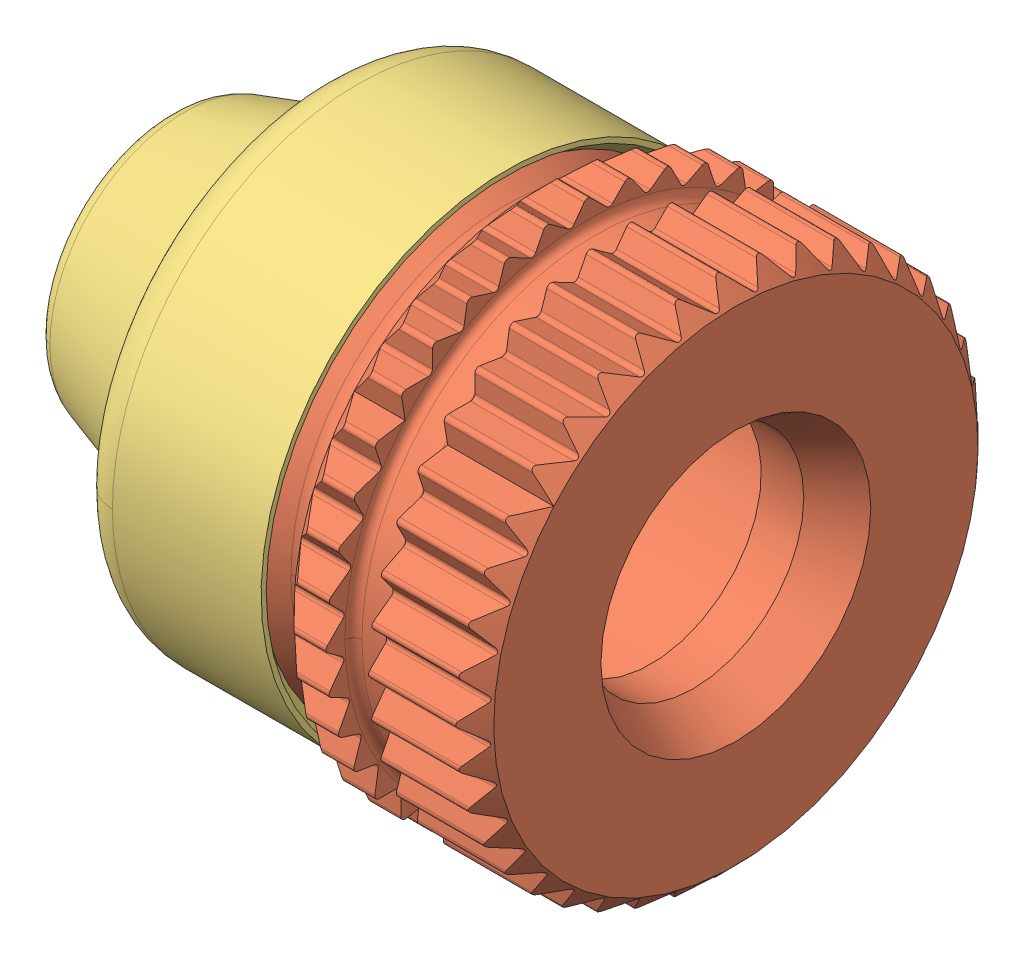
SolidWorks assembly Southco-D8-334-100-300, configuration Default. Lengths in mm.
Overall size (13.4 12.29 12.29).
3 component instances, 3 part files, 0 mates.
Components (placement in the parent):
- SW3dPS-D8-334-100-300_TAB PLATE-1: SW3dPS-D8-334-100-300_TAB PLATE [Default] at (3 0 0) x (0 -1 0) z (0 0 1) size (9.5 1.42 8)
- SW3dPS-D8-334-100-300_D3_PANEX_Front_Mount_Insert_Body-1: SW3dPS-D8-334-100-300_D3_PANEX_Front_Mount_Insert_Body [Default] at (0.1 0 0) x (1 0 0) z (0 -1 0) size (9.3 12.29 12.29)
- SW3dPS-D8-334-100-300_D3_PANEX_Insert_Cup-1: SW3dPS-D8-334-100-300_D3_PANEX_Insert_Cup [Default] at origin size (8 11.55 11.55)
